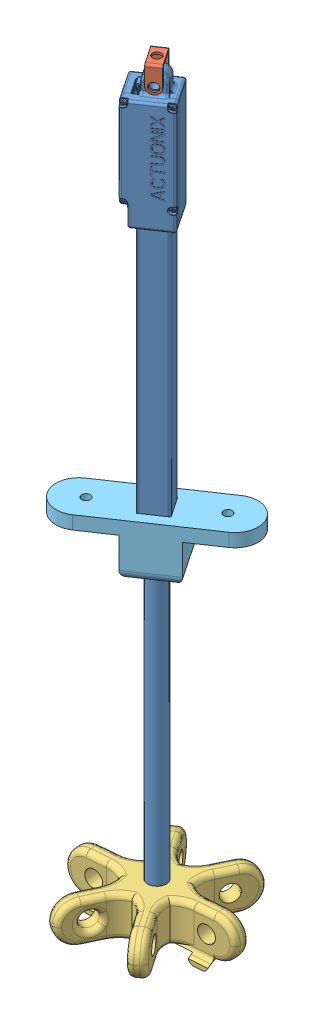
SolidWorks assembly ACT - A01 - actuator with bracket, configuration Default. Lengths in mm.
Overall size (81.32 365.03 73.53).
5 component instances, 5 part files, 11 mates.
Components (placement in the parent):
- l16_140mm_out-1: l16_140mm_out [Default] at (18.5459 -55.4 291.5023) x (0.55973 0 0.828675) z (-0.828675 0 0.55973) size (20.03 356.4 20.21)
- rear_actuatorbracket-1: rear_actuatorbracket [Default] at (12.7379 4.8 288.4866) x (0.55973 0 0.828675) z (0.828675 0 -0.55973) size (11.5 12.43 6.25)
- ACT - P01 - actuator sliding mechanism bracket - full channel-1: ACT - P01 - actuator sliding mechanism bracket - full channel [Default] at (18.5459 -337.1976 291.5023) x (-0.079203 0 -0.996859) z (-0.996859 0 0.079203) size (67.7 23.18 76.2)
- 91772A247_18-8 SS PAN HEAD PHILLIPS MACHINE SCREW-1: 91772A247_18-8 SS PAN HEAD PHILLIPS MACHINE SCREW [91772A247] at (18.5459 -326.62 291.5023) x (1 0 0) z (0 -1 0) size (9.47 9.47 29.24)
- FRA - P04-1: FRA - P04 [Default] at (12.4096 -182 282.3729) x (-0.828675 0 0.55973) z (0 1 0) size (76 22 25.4)
Mates (geometry in assembly coordinates):
- Coincident2: coincident aligned: plane of l16_140mm_out-1 through (25.5896 0 286.7446) normal (0 1 0)
- Width1: width: plane of rear_actuatorbracket-1 through (23.7942 3.8 293.6893) normal (-0.55973 0 -0.828675); plane of rear_actuatorbracket-1 through (18.4768 -7.625 285.8169) normal (0.55973 0 0.828675); cylinder of l16_140mm_out-1 through (18.5459 -200.4 291.5023) axis (0 -1 0) radius 4.475
- Concentric19: concentric aligned: cylinder of l16_140mm_out-1 through (20.7848 -4.5 294.817) axis (-0.55973 0 -0.828675) radius 2.125; cylinder of rear_actuatorbracket-1 through (21.7644 -4.5 296.2672) axis (-0.55973 0 -0.828675) radius 2.125
- Parallel2: parallel aligned: plane of l16_140mm_out-1 through (14.0537 -9 305.3973) normal (-0.828675 0 0.55973); plane of rear_actuatorbracket-1 through (12.7379 4.8 288.4866) normal (-0.828675 0 0.55973)
- Concentric21: concentric aligned: cylinder of l16_140mm_out-1 through (18.5459 -200.4 291.5023) axis (0 -1 0) radius 4.475; cylinder of ACT - P01 - actuator sliding mechanism bracket - full channel-1 through (18.5459 -356.4 291.5023) axis (0 -1 0) radius 3.3
- Tangent3: tangent aligned: cylinder of l16_140mm_out-1 through (16.0271 -345.775 287.7733) axis (0.55973 0 0.828675) radius 10.625; plane of ACT - P01 - actuator sliding mechanism bracket - full channel-1 through (18.5459 -356.4 291.5023) normal (0 -1 0)
- Concentric22: concentric anti-aligned: cylinder of ACT - P01 - actuator sliding mechanism bracket - full channel-1 through (18.5459 -356.4 291.5023) axis (0 -1 0) radius 7.275; cylinder of 91772A247_18-8 SS PAN HEAD PHILLIPS MACHINE SCREW-1 through (18.5459 -326.62 291.5023) axis (0 1 0) radius 4.7371
- Coincident4: coincident anti-aligned: plane of ACT - P01 - actuator sliding mechanism bracket - full channel-1 through (18.2845 -352.02 288.2127) normal (0 -1 0); plane of 91772A247_18-8 SS PAN HEAD PHILLIPS MACHINE SCREW-1 through (18.5459 -352.02 291.5023) normal (0 1 0)
- Coincident6: coincident anti-aligned: plane of l16_140mm_out-1 through (16.9322 -55.4 299.8327) normal (-0.828675 0 0.55973); plane of FRA - P04-1 through (16.9322 -182 299.8327) normal (0.828675 0 -0.55973)
- Coincident8: coincident anti-aligned: plane of l16_140mm_out-1 through (10.2155 -55.4 289.8886) normal (-0.55973 0 -0.828675); plane of FRA - P04-1 through (10.2155 -182 289.8886) normal (0.55973 0 0.828675)
- Coincident9: coincident aligned: plane of l16_140mm_out-1 through (18.5459 -207.4 291.5023) normal (0 -1 0); plane of FRA - P04-1 through (15.6082 -207.4 306.7608) normal (0 -1 0)
